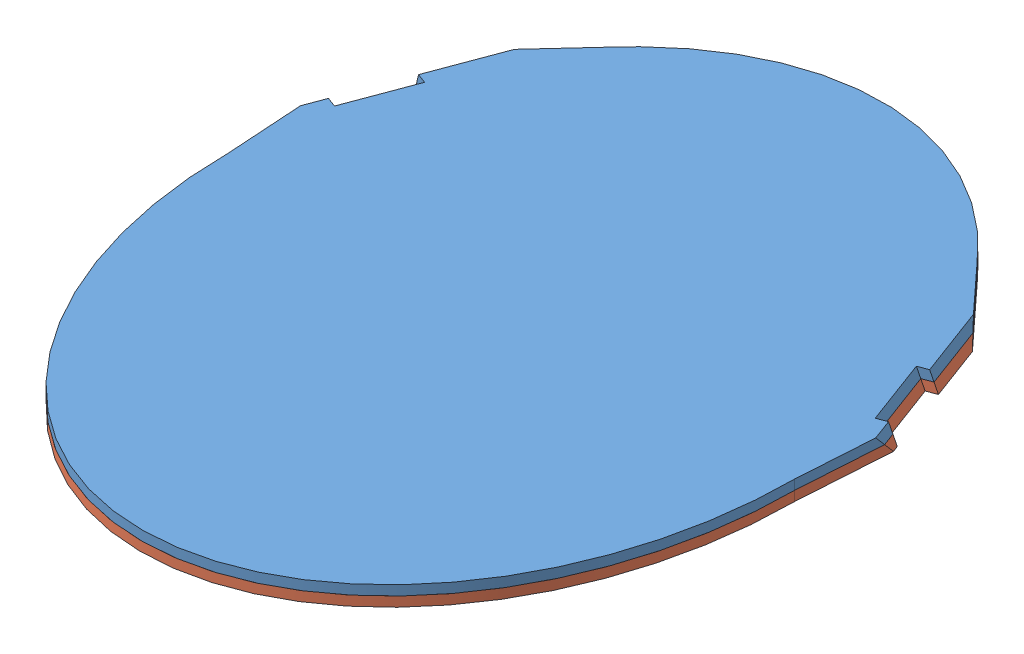
SolidWorks assembly Secondary Mirror, configuration Default. Lengths in mm.
Overall size (853.84 47.7 760).
3 component instances, 3 part files, 6 mates.
Components (placement in the parent):
- Secondary Mirror Back-1: Secondary Mirror Back [Default] at (-136.2253 113.5977 -8.6893) size (591.15 44.84 760)
- Secondary Mirror Front-1: Secondary Mirror Front [Default] at (-136.2253 113.5977 -8.6893) x (-1 0 0) z (0 0 1) size (592.25 10 760)
- Secondary Mirror-1: Secondary Mirror [Default] at (-136.2253 113.5977 -8.6893) x (-1 0 0) z (0 0 1) size (832.72 4 730)
Mates (geometry in assembly coordinates):
- Coincident2: coincident anti-aligned: plane of Secondary Mirror Back-1 through (-136.2253 113.5977 -8.6893) normal (0 -1 0); plane of Secondary Mirror Front-1 through (-136.2253 113.5977 -8.6893) normal (0 1 0)
- Coincident3: coincident aligned: plane of Secondary Mirror Back-1 through (-136.2253 113.5977 -8.6893) normal (0 0 1); plane of Secondary Mirror Front-1 through (-136.2253 113.5977 -8.6893) normal (0 0 1)
- Coincident4: coincident anti-aligned: plane of Secondary Mirror Back-1 through (-136.2253 113.5977 -8.6893) normal (1 0 0); plane of Secondary Mirror Front-1
- Coincident5: coincident anti-aligned: plane of Secondary Mirror Back-1 through (-136.2253 113.5977 -8.6893) normal (1 0 0); plane of Secondary Mirror-1
- Coincident6: coincident aligned: plane of Secondary Mirror Back-1 through (-136.2253 113.5977 -8.6893) normal (0 0 1); plane of Secondary Mirror-1 through (-136.2253 113.5977 -8.6893) normal (0 0 1)
- Coincident8: coincident anti-aligned: plane of Secondary Mirror Back-1 through (-136.2253 113.5977 -8.6893) normal (0 -1 0); plane of Secondary Mirror-1 through (-136.2253 113.5977 -8.6893) normal (0 1 0)
